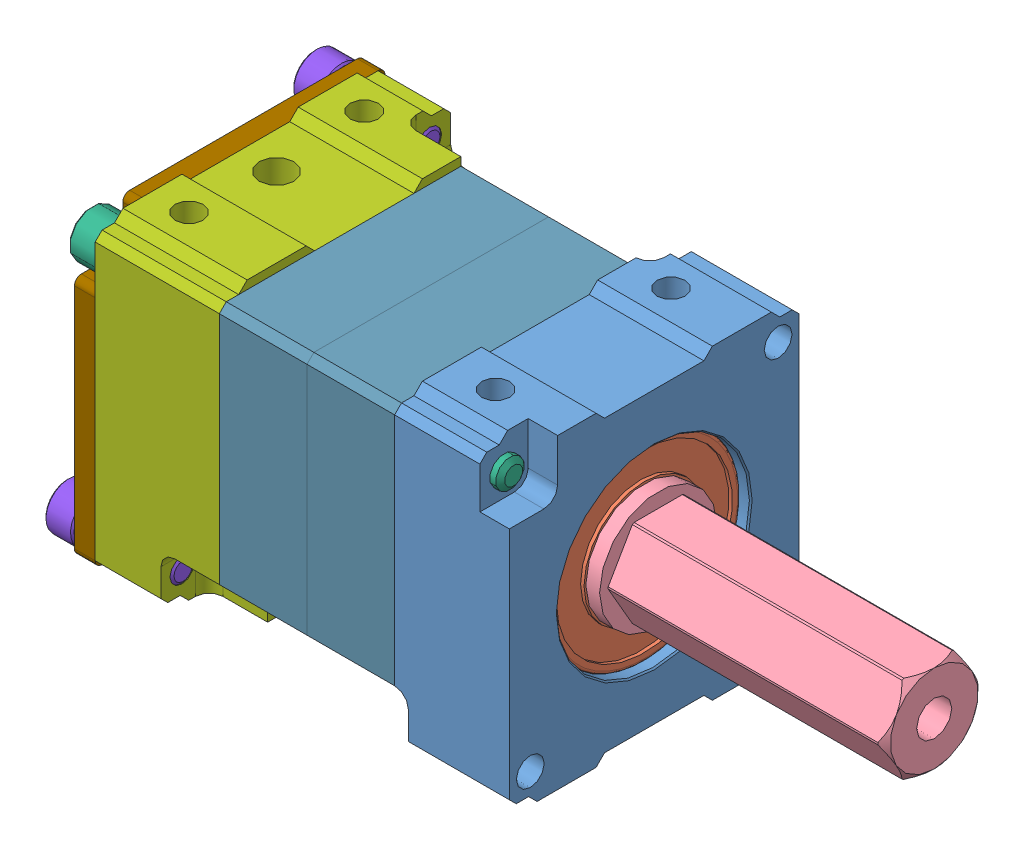
SolidWorks assembly Gearbox, configuration Default. Lengths in mm.
Overall size (107.66 49.05 49.3).
37 component instances, 17 part files, 0 mates.
Components (placement in the parent):
- 217-2625-026 Rev1-1: 217-2625-026 Rev1 [Default] at (-6.5 22.225 0) x (0 -1 0) z (-1 0 0) size (44.45 42 18.13)
- 217-2742-001 Rev4-1: 217-2742-001 Rev4 [Default] at (0.2002 22.225 0) x (1 0 0) z (0 -0.092627 0.995701) size (7 28 28)
- 217-2742-001 Rev4-2: 217-2742-001 Rev4 [Default] at (8.2002 22.225 0) size (7 28 28)
- 217-2625-017 Rev1_9714K61-1: 217-2625-017 Rev1_9714K61 [Default] at (7.42 22.3002 -0.342) x (0 0.56703 0.823697) z (0 -0.823697 0.56703) size (28.51 4.98 30.18)
- 217-2625-003 Rev1-1: 217-2625-003 Rev1 [Default] at (7.4478 22.225 0) x (0 -1 0) z (1 0 0) size (17 17 64.12)
- 217-2625-018 Rev1_98541A410-1: 217-2625-018 Rev1_98541A410 [Default] at (-0.7046 22.225 0) x (1 0 0) z (0 -0.017452 0.999848) size (1 19.6 17.4)
- 832-2250-Base-Kit-Screw_SSA0832-0500ZC-1: 832-2250-Base-Kit-Screw_SSA0832-0500ZC [Default] at (-43.4 4.725 -17.5) x (0 -0.767799 -0.640691) z (0 0.640691 -0.767799) size (6.73 61.21 6.73)
- 832-2250-Base-Kit-Screw_SSA0832-0500ZC-2: 832-2250-Base-Kit-Screw_SSA0832-0500ZC [Default] at (-43.4 39.725 17.5) x (0 0.961307 0.275478) z (0 -0.275478 0.961307) size (6.73 61.21 6.73)
- 217-2625-025 Rev1-1: 217-2625-025 Rev1 [Default] at (-35.9 22.225 0) x (0 -1 0) z (-1 0 0) size (44.45 42 18)
- 217-4649-002 Rev1_SSA0832-0500ZC-1: 217-4649-002 Rev1_SSA0832-0500ZC [Default] at (-46.4 4.2645 17.9605) x (0 0.33842 -0.940995) z (0 0.940995 0.33842) size (6.73 16.76 6.73)
- 217-4649-002 Rev1_SSA0832-0500ZC-2: 217-4649-002 Rev1_SSA0832-0500ZC [Default] at (-46.4 40.1855 -17.9605) x (0 -0.308932 -0.951084) z (0 0.951084 -0.308932) size (6.73 16.76 6.73)
- 217-2822-003 Rev4-1: 217-2822-003 Rev4 [Default] at (-44.9 22.225 0) x (0 -1 0) z (-1 0 0) size (42 42 4.8)
- 217-2820 Rev1_Public-1: 217-2820 Rev1_Public [Default] at (-4.6546 22.225 0) x (0 -0.456494 0.889726) z (-1 0 0) size (39.26 38.9 17.4)
  - 217-2625-100-1: 217-2625-100 [Default] at origin size (39.26 38.9 12.7)
    - 217-2625-008 Rev1-1: 217-2625-008 Rev1 [Default] at origin size (34.7 34.7 4.7)
    - 217-2625-010 Rev1-1: 217-2625-010 Rev1 [Default] at (0 10.193 3.65) x (0.999813 0.019336 0) z (0 0 1) size (4 4 12)
    - 217-2625-010 Rev1-2: 217-2625-010 Rev1 [Default] at (8.691 -5.3258 3.65) size (4 4 12)
    - 217-2625-010 Rev1-3: 217-2625-010 Rev1 [Default] at (-8.691 -5.3258 3.65) size (4 4 12)
    - 217-2625-005 Rev1_Planet_Revolving_Follower01-1: 217-2625-005 Rev1_Planet_Revolving_Follower01 [Default] at (8.691 -5.3258 6.35) x (0.932816 0.360354 0) z (0 0 1) size (16.91 16.92 8)
    - 217-2625-005 Rev1_Planet_Revolving_Follower01-2: 217-2625-005 Rev1_Planet_Revolving_Follower01 [Default] at (-8.691 -5.3258 6.35) x (-0.932788 -0.360426 0) z (0 0 1) size (16.91 16.92 8)
    - 217-2625-005 Rev1_Planet_Revolving_Follower01-3: 217-2625-005 Rev1_Planet_Revolving_Follower01 [Default] at (0 10.193 6.35) x (0.893583 0.448898 0) z (0 0 1) size (16.91 16.92 8)
  - 217-2625-007 Rev1_Public-1: 217-2625-007 Rev1_Public [Default] at (0 0 6.7) x (0.992772 0.120019 0) z (0 0 1) size (14.49 14.49 12.72)
- 217-2816-001 Rev1-1: 217-2816-001 Rev1 [Default] at (-6.35 22.225 0) x (0 -1 0) z (1 0 0) size (42 42 14.5)
- 217-2820 Rev1_Public-2: 217-2820 Rev1_Public [Default] at (-17.15 22.225 0) x (0 0.184082 0.982911) z (-1 0 0) size (39.26 38.9 17.4)
  - 217-2625-100-1: 217-2625-100 [Default] at origin size (39.26 38.9 12.7)
    - 217-2625-008 Rev1-1: 217-2625-008 Rev1 [Default] at origin size (34.7 34.7 4.7)
    - 217-2625-010 Rev1-1: 217-2625-010 Rev1 [Default] at (0 10.193 3.65) x (0.999813 0.019336 0) z (0 0 1) size (4 4 12)
    - 217-2625-010 Rev1-2: 217-2625-010 Rev1 [Default] at (8.691 -5.3258 3.65) size (4 4 12)
    - 217-2625-010 Rev1-3: 217-2625-010 Rev1 [Default] at (-8.691 -5.3258 3.65) size (4 4 12)
    - 217-2625-005 Rev1_Planet_Revolving_Follower01-1: 217-2625-005 Rev1_Planet_Revolving_Follower01 [Default] at (8.691 -5.3258 6.35) x (0.932816 0.360354 0) z (0 0 1) size (16.91 16.92 8)
    - 217-2625-005 Rev1_Planet_Revolving_Follower01-2: 217-2625-005 Rev1_Planet_Revolving_Follower01 [Default] at (-8.691 -5.3258 6.35) x (-0.932788 -0.360426 0) z (0 0 1) size (16.91 16.92 8)
    - 217-2625-005 Rev1_Planet_Revolving_Follower01-3: 217-2625-005 Rev1_Planet_Revolving_Follower01 [Default] at (0 10.193 6.35) x (0.893583 0.448898 0) z (0 0 1) size (16.91 16.92 8)
  - 217-2625-007 Rev1_Public-1: 217-2625-007 Rev1_Public [Default] at (0 0 6.7) x (0.992772 0.120019 0) z (0 0 1) size (14.49 14.49 12.72)
- 217-2816-001 Rev1-2: 217-2816-001 Rev1 [Default] at (-19.05 22.225 0) x (0 -1 0) z (1 0 0) size (42 42 14.5)
- 217-4649-001 Rev1-1: 217-4649-001 Rev1 [Default] at (-32.746 22.225 0) x (0 -1 0) z (1 0 0) size (18 18 13)
- 217-4649-007 Rev1_94105A824-1: 217-4649-007 Rev1_94105A824 [Default] at (-38.221 22.225 -6.7835) x (-0.996104 -0.088191 0) z (0 0 -1) size (4.83 4.83 4.9)
- 217-2625-011 Rev1-1: 217-2625-011 Rev1 [Default] at (-37.4818 22.225 0) x (0 0 1) z (0 -1 0) size (8.01 7.5 7.94)
